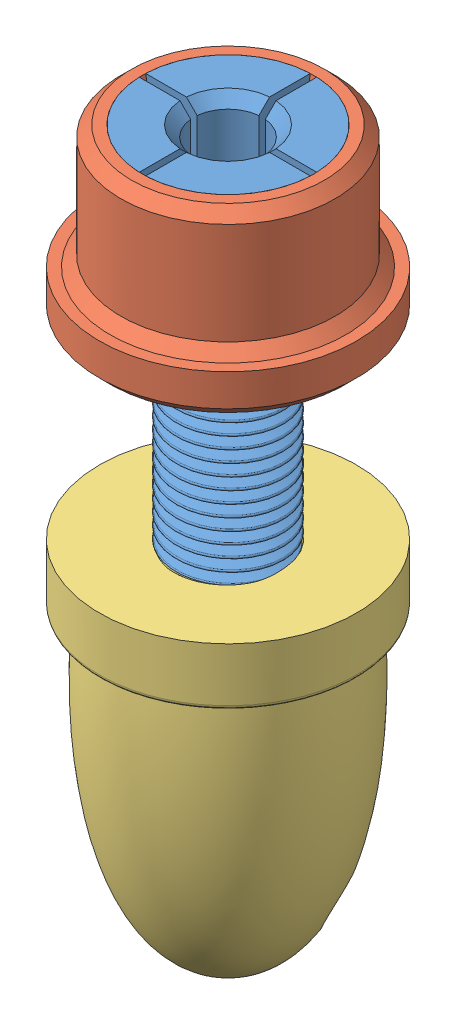
SolidWorks assembly Spinner M5, configuration Défaut. Lengths in mm.
Overall size (16.5 33.75 16.5).
3 component instances, 3 part files, 7 mates.
Components (placement in the parent):
- SPINNER V1 - Axe M5-1: SPINNER V1 - Axe M5 [Défaut] x (0 0 1) z (1 0 0) size (7.99 23.53 7.99)
- SPINNER V1 - Bloc M5-1: SPINNER V1 - Bloc M5 [Default] at (0 -7.75 0) x (0.864523 0 -0.502594) z (0.502594 0 0.864523) size (12 7.75 12)
- SPINNER V1 - Tête M5-1: SPINNER V1 - Tête M5 [Default] at (0 -16.75 0) x (0.523185 0 0.852219) z (0.852219 0 -0.523185) size (12 17.25 12)
Mates (geometry in assembly coordinates):
- Coïncidente11: coincident aligned: plane of SPINNER V1 - Axe M5-1 through (0 0 -2.1) normal (0 1 0); plane of assembly through (0 0 0) normal (0 1 0)
- Coaxiale1: concentric aligned: cone of SPINNER V1 - Axe M5-1 through (0 -6 0) axis (0 -1 0); cone of SPINNER V1 - Bloc M5-1 through (0 0 0) axis (0 -1 0)
- Coaxiale2: concentric: cylinder of SPINNER V1 - Bloc M5-1 through (0 -44.7103 0) axis (0 -1 0) radius 6; cylinder of SPINNER V1 - Tête M5-1 through (0 -25.36 0) axis (0 1 0) radius 6
- Coïncidente12: coincident aligned: plane of SPINNER V1 - Axe M5-1 through (0 0 -2.1) normal (0 1 0); plane of SPINNER V1 - Bloc M5-1 through (4.3226 0 -2.513) normal (0 1 0)
- Coïncidente13: coincident aligned: plane of SPINNER V1 - Axe M5-1 through (0 0 0) normal (1 0 0); plane of assembly through (0 0 0) normal (1 0 0)
- Coïncidente15: coincident aligned: plane of SPINNER V1 - Axe M5-1; plane of assembly through (0 0 0) normal (0 0 1)
- Distance1: distance = 9 mm anti-aligned: plane of SPINNER V1 - Bloc M5-1 through (2.7232 -7.75 -1.5832) normal (0 -1 0); plane of SPINNER V1 - Tête M5-1 through (0 -16.75 0) normal (0 1 0)
